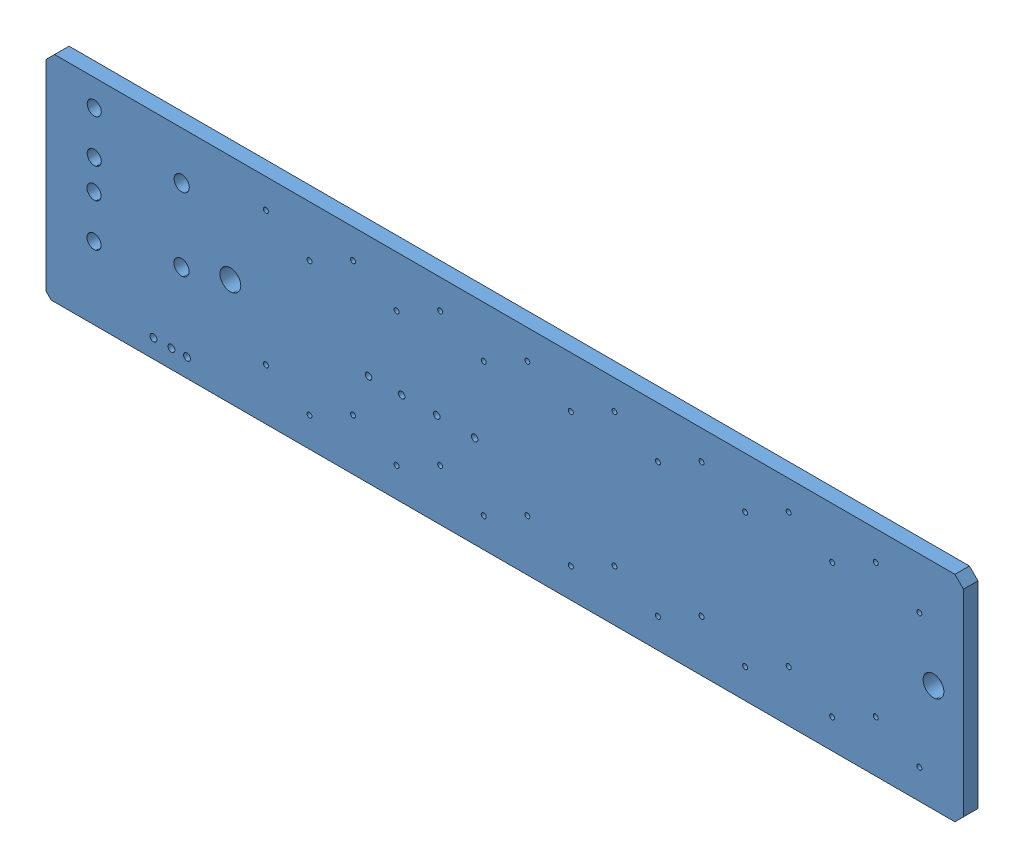
SolidWorks assembly RHD2132_headstage1_revC, configuration Default. Lengths in mm.
Overall size (108.6 25 14.7).
23 component instances, 8 part files, 0 mates.
Components (placement in the parent):
- Board_1-1: Board_1 [Default] at (0 0 -1.6916) size (107 25 1.69)
- J3-1: J3 [Default] at origin size (19.05 7.9 7.4) (hidden)
  - Jack_PCB-1: Jack_PCB [Default] at (7.9749 19.4619 4) x (-1 0 0) z (0 1 0) size (19.05 7.4 7.9)
- J4-1: J4 [Default] at origin size (19.05 7.9 7.4) (hidden)
  - Jack_PCB-1: Jack_PCB [Default] at (7.9499 10.9619 4) x (-1 0 0) z (0 1 0) size (19.05 7.4 7.9)
- J1-1: J1 [Default] at origin size (86.5 7.28 11.56) (hidden)
  - wire_connector-1: wire_connector [Default] at (18.525 4.6649 3.4087) x (1 0 0) z (0 -1 0) size (86.5 9.6 7.28)
  - mill-max-0908-2-15-20-75-14-11-0-1: mill-max-0908-2-15-20-75-14-11-0 [Default] at (102.9839 2.6516 1.27) x (0 0 1) z (1 0 0) size (3.33 1.01 1.01)
    - mill-max-0908-2-15-20-75-14-11-0_SPRING-1: mill-max-0908-2-15-20-75-14-11-0_SPRING [Default] at (5.5978 -0.8235 -1.1087) x (0 -0.998082 0.061903) z (-1 0 0) size (0.96 0.96 3.33)
  - mill-max-0908-2-15-20-75-14-11-0_1-1: mill-max-0908-2-15-20-75-14-11-0_1 [Default] at (102.9839 2.6516 1.27) x (0 0 1) z (1 0 0) size (9.22 1.83 1.83)
    - mill-max-0908-2-15-20-75-14-11-0_0963-0_0963-0-00-20-00-00-13-0-1: mill-max-0908-2-15-20-75-14-11-0_0963-0_0963-0-00-20-00-00-13-0 [Default] at (0.1795 -0.8235 -1.1087) size (4.04 1.31 1.31)
    - mill-max-0908-2-15-20-75-14-11-0_0954-0_0954-0-00-20-00-00-13-0-1: mill-max-0908-2-15-20-75-14-11-0_0954-0_0954-0-00-20-00-00-13-0 [Default] at (1.9321 -0.8235 -1.1087) size (5.03 1.83 1.83)
    - mill-max-0908-2-15-20-75-14-11-0_SPRING_0975-0-00-00-75-14-45-0-1: mill-max-0908-2-15-20-75-14-11-0_SPRING_0975-0-00-00-75-14-45-0 [Default] at (5.5978 -0.8235 -1.1087) x (0 -0.998082 0.061903) z (-1 0 0) size (0.8 0.8 3.43)
    - mill-max-0908-2-15-20-75-14-11-0_0918-X_0918-7-00-20-00-00-13-0-1: mill-max-0908-2-15-20-75-14-11-0_0918-X_0918-7-00-20-00-00-13-0 [Default] at (3.9133 -0.8235 -1.1087) x (1 0 0) z (0 0.540629 0.841261) size (5.49 1.25 1.25)
- J2-1: J2 [Default] at origin size (86.5 7.28 11.56) (hidden)
  - wire_connector-1: wire_connector [Default] at (18.525 20.2649 3.4087) x (1 0 0) z (0 -1 0) size (86.5 9.6 7.28)
  - mill-max-0908-2-15-20-75-14-11-0-1: mill-max-0908-2-15-20-75-14-11-0 [Default] at (102.9839 18.2516 1.27) x (0 0 1) z (1 0 0) size (3.33 1.01 1.01)
    - mill-max-0908-2-15-20-75-14-11-0_SPRING-1: mill-max-0908-2-15-20-75-14-11-0_SPRING [Default] at (5.5978 -0.8235 -1.1087) x (0 -0.998082 0.061903) z (-1 0 0) size (0.96 0.96 3.33)
  - mill-max-0908-2-15-20-75-14-11-0_1-1: mill-max-0908-2-15-20-75-14-11-0_1 [Default] at (102.9839 18.2516 1.27) x (0 0 1) z (1 0 0) size (9.22 1.83 1.83)
    - mill-max-0908-2-15-20-75-14-11-0_0963-0_0963-0-00-20-00-00-13-0-1: mill-max-0908-2-15-20-75-14-11-0_0963-0_0963-0-00-20-00-00-13-0 [Default] at (0.1795 -0.8235 -1.1087) size (4.04 1.31 1.31)
    - mill-max-0908-2-15-20-75-14-11-0_0954-0_0954-0-00-20-00-00-13-0-1: mill-max-0908-2-15-20-75-14-11-0_0954-0_0954-0-00-20-00-00-13-0 [Default] at (1.9321 -0.8235 -1.1087) size (5.03 1.83 1.83)
    - mill-max-0908-2-15-20-75-14-11-0_SPRING_0975-0-00-00-75-14-45-0-1: mill-max-0908-2-15-20-75-14-11-0_SPRING_0975-0-00-00-75-14-45-0 [Default] at (5.5978 -0.8235 -1.1087) x (0 -0.998082 0.061903) z (-1 0 0) size (0.8 0.8 3.43)
    - mill-max-0908-2-15-20-75-14-11-0_0918-X_0918-7-00-20-00-00-13-0-1: mill-max-0908-2-15-20-75-14-11-0_0918-X_0918-7-00-20-00-00-13-0 [Default] at (3.9133 -0.8235 -1.1087) x (1 0 0) z (0 0.540629 0.841261) size (5.49 1.25 1.25)
